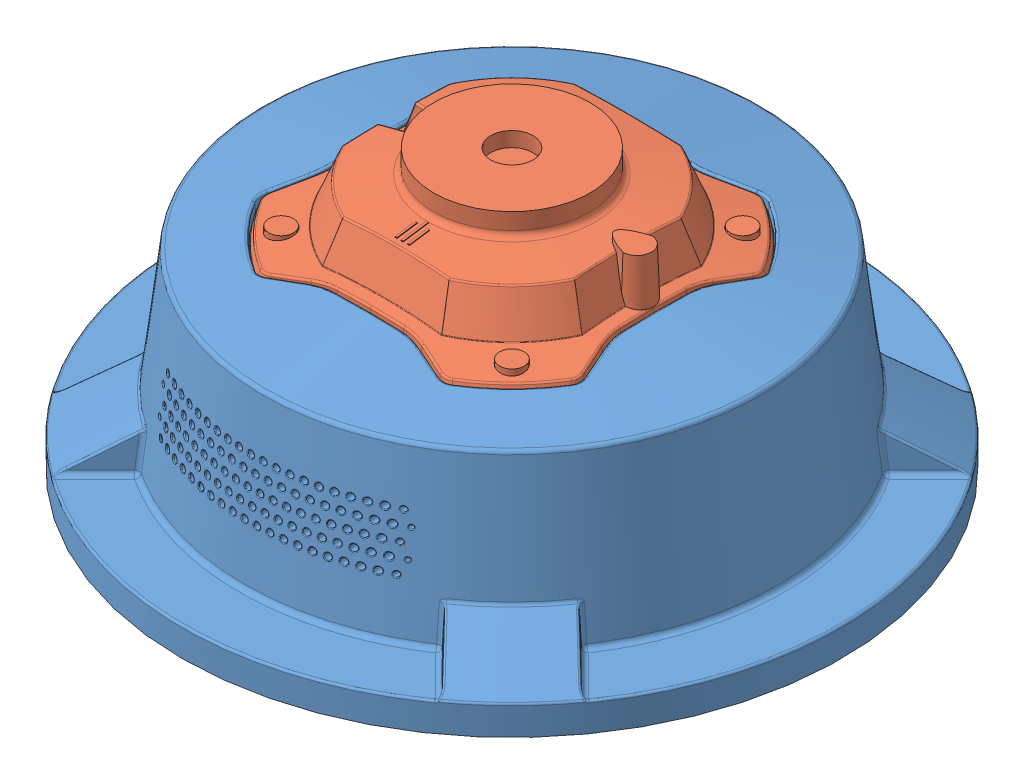
SolidWorks assembly Mirobot_Base, configuration 默认. Lengths in mm.
Overall size (160 67.39 160).
2 component instances, 2 part files, 1 mates.
Components (placement in the parent):
- 01固定座底壳-1: 01固定座底壳 [默认] at (-0.266 20.3702 160.0008) x (1 0 0) z (0 1 0) size (160 160 50.86)
- 03连接底座-2: 03连接底座 [默认] at (-50.0172 22.0959 160.0008) x (0 0 1) z (0 1 0) size (80.02 80.02 20.82)
Mates (geometry in assembly coordinates):
- 重合1: coincident anti-aligned: plane of 01固定座底壳-1 through (-49.766 21.836 151.9622) normal (0 1 0); plane of 03连接底座-2 through (-0.266 21.836 115.0008) normal (0 -1 0)
